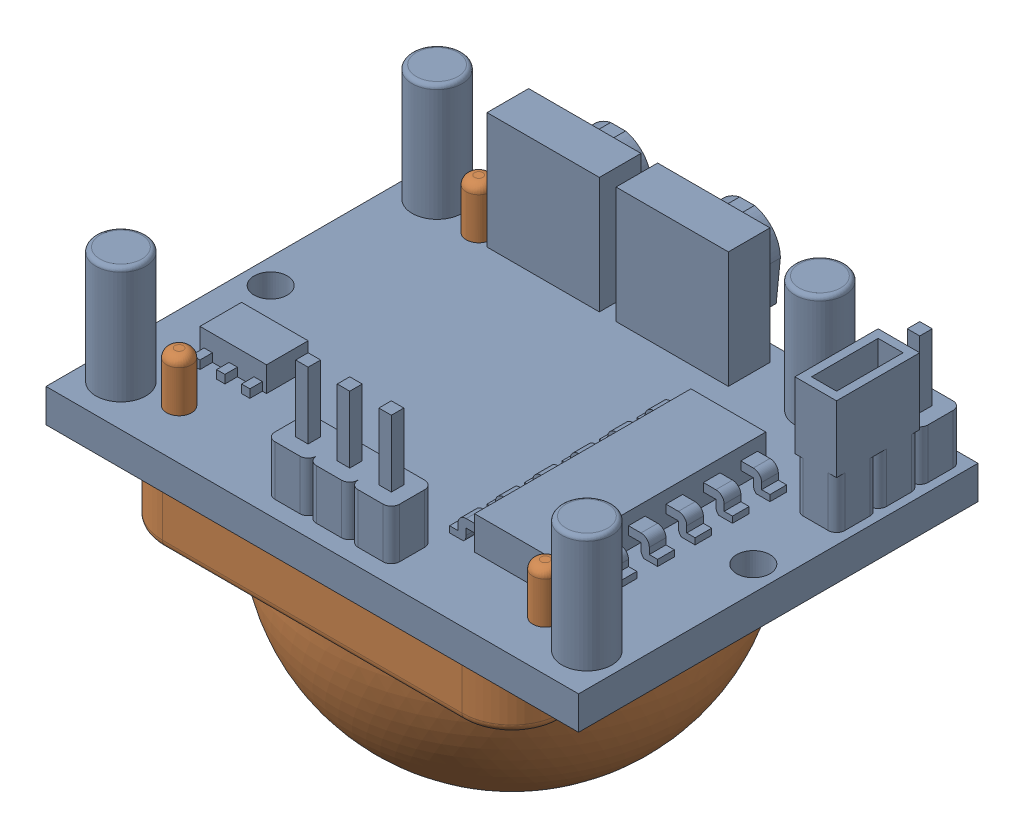
SolidWorks assembly PIRSLDASM, configuration Default. Lengths in mm.
Overall size (32 23.5 25).
2 component instances, 2 part files, 0 mates.
Components (placement in the parent):
- sensor-1: sensor [Default] at (-0.2067 11.0548 34.2903) size (32 15 25)
- lens-1: lens [Default] at (-0.2067 10.0548 34.2903) x (-1 0 0) z (0 0 1) size (24 19.5 24)
